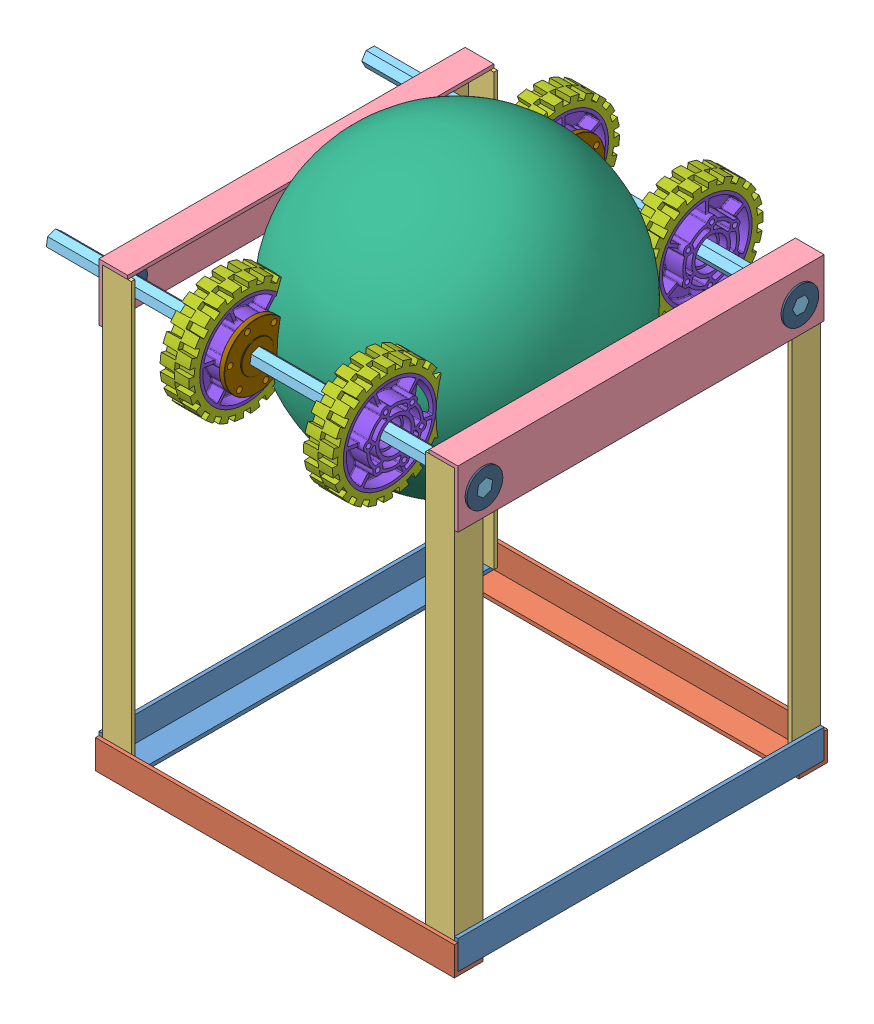
SolidWorks assembly shooter assembly, configuration Default. Lengths in mm.
Overall size (381 483.45 421.01).
33 component instances, 10 part files, 67 mates.
Components (placement in the parent):
- width angle bracket-5: width angle bracket [Default] at origin size (25.4 25.4 323.85)
- width angle bracket-6: width angle bracket [Default] at (317.5 0 323.85) x (-1 0 0) z (0 0 -1) size (25.4 25.4 323.85)
- height angle bracket-1: height angle bracket [Default] at (0 -3.175 327.025) x (0 0 -1) z (1 0 0) size (25.4 25.4 317.5)
- height angle bracket-2: height angle bracket [Default] at (317.5 -3.175 -3.175) x (0 0 1) z (-1 0 0) size (25.4 25.4 317.5)
- length angle bracket-5: length angle bracket [Default] at (314.325 3.175 323.85) x (0 0 -1) z (0 1 0) size (25.4 25.4 381)
- length angle bracket-6: length angle bracket [Default] at (3.175 3.175 323.85) x (1 0 0) z (0 1 0) size (25.4 25.4 381)
- length angle bracket-7: length angle bracket [Default] at (3.175 384.175 0) x (1 0 0) z (0 -1 0) size (25.4 25.4 381)
- length angle bracket-8: length angle bracket [Default] at (314.325 384.175 0) x (0 0 1) z (0 -1 0) size (25.4 25.4 381)
- front width angle-3: front width angle [Default] at (317.5 387.35 323.85) x (0 -1 0) z (0 0 -1) size (50.8 25.4 323.85)
- front width angle-4: front width angle [Default] at (0 387.35 0) x (0 -1 0) z (0 0 1) size (50.8 25.4 323.85)
- shaft-2: shaft [Default] at (319.0748 360.3625 22.225) x (0 -0.036855 -0.999321) z (-1 0 0) size (14.66 12.7 381)
- shaft-3: shaft [Default] at (319.0748 360.3625 301.625) x (0 0.344018 -0.938963) z (-1 0 0) size (14.66 12.7 381)
- ball-1: ball [Default] at (154.804 353.2764 162.3949) size (254 254 254)
- 4 in HiGrip Wheel-1: 4 in HiGrip Wheel [Default] at (103.3017 363.8336 21.178) x (1 0 0) z (0 -0.883864 -0.467743) size (35.12 101.6 101.6)
  - 4 in tread-1: 4 in tread [Default] at (-8.0517 2.5236 2.5343) size (25.4 101.6 101.6)
  - 4in 2013 Hub-1: 4in 2013 Hub [Default] at (-8.0517 2.5236 2.5343) size (35.12 82.55 82.55)
- 4 in HiGrip Wheel-2: 4 in HiGrip Wheel [Default] at (230.3017 361.1665 18.7111) x (1 0 0) z (0 -0.84701 0.531577) size (35.12 101.6 101.6)
  - 4 in tread-1: 4 in tread [Default] at (-8.0517 2.5236 2.5343) size (25.4 101.6 101.6)
  - 4in 2013 Hub-1: 4in 2013 Hub [Default] at (-8.0517 2.5236 2.5343) size (35.12 82.55 82.55)
- 4 in HiGrip Wheel-3: 4 in HiGrip Wheel [Default] at (230.3017 362.3873 298.7367) x (1 0 0) z (0 -0.985175 0.171553) size (35.12 101.6 101.6)
  - 4 in tread-1: 4 in tread [Default] at (-8.0517 2.5236 2.5343) size (25.4 101.6 101.6)
  - 4in 2013 Hub-1: 4in 2013 Hub [Default] at (-8.0517 2.5236 2.5343) size (35.12 82.55 82.55)
- 4 in HiGrip Wheel-4: 4 in HiGrip Wheel [Default] at (103.3017 356.8299 301.2931) x (1 0 0) z (0 0.641157 0.76741) size (35.12 101.6 101.6)
  - 4 in tread-1: 4 in tread [Default] at (-8.0517 2.5236 2.5343) size (25.4 101.6 101.6)
  - 4in 2013 Hub-1: 4in 2013 Hub [Default] at (-8.0517 2.5236 2.5343) size (35.12 82.55 82.55)
- am-0096a+500+Hex+Hub+r2-1: am-0096a+500+Hex+Hub+r2 [Default] at (218.7116 360.3235 301.6576) x (1 0 0) z (0 -0.76741 0.641157) size (25.4 57.15 57.15)
- am-0096a+500+Hex+Hub+r2-2: am-0096a+500+Hex+Hub+r2 [Default] at (218.7116 360.3614 22.1957) x (1 0 0) z (0 -0.467743 0.883864) size (25.4 57.15 57.15)
- am-0096a+500+Hex+Hub+r2-3: am-0096a+500+Hex+Hub+r2 [Default] at (98.7884 360.3914 301.62) x (-1 0 0) z (0 0.76741 -0.641157) size (25.4 57.15 57.15)
- am-0096a+500+Hex+Hub+r2-4: am-0096a+500+Hex+Hub+r2 [Default] at (98.7884 360.4133 22.2231) x (-1 0 0) z (0 -0.999321 0.036855) size (25.4 57.15 57.15)
- .5in hex bearing-1: .5in hex bearing [Default] at (311.15 360.3625 22.225) x (0 0.036855 0.999321) z (0 0.999321 -0.036855) size (31.72 7.92 31.72)
- .5in hex bearing-2: .5in hex bearing [Default] at (311.15 360.3625 301.625) x (0 0.344018 -0.938963) z (0 -0.938963 -0.344018) size (31.72 7.92 31.72)
- .5in hex bearing-3: .5in hex bearing [Default] at (6.35 360.3625 301.625) x (0 -0.985175 0.171553) z (0 -0.171553 -0.985175) size (31.72 7.92 31.72)
- .5in hex bearing-4: .5in hex bearing [Default] at (6.35 360.3625 22.225) x (0 -0.036855 -0.999321) z (0 0.999321 -0.036855) size (31.72 7.92 31.72)
Mates (geometry in assembly coordinates):
- Coincident2: coincident aligned: plane of width angle bracket-5 through (0 0 323.85) normal (-1 0 0); plane of height angle bracket-1 through (0 -3.175 327.025) normal (-1 0 0)
- Coincident3: coincident anti-aligned: plane of width angle bracket-5 through (0 0 323.85) normal (0 0 1); plane of height angle bracket-1 through (317.5 22.225 323.85) normal (0 0 -1)
- Coincident4: coincident anti-aligned: plane of width angle bracket-5 through (0 0 323.85) normal (0 -1 0); plane of height angle bracket-1 through (317.5 0 301.625) normal (0 1 0)
- Coincident7: coincident anti-aligned: plane of width angle bracket-6 through (317.5 0 323.85) normal (0 0 1); plane of height angle bracket-1 through (317.5 22.225 323.85) normal (0 0 -1)
- Coincident8: coincident anti-aligned: plane of width angle bracket-6 through (317.5 0 0) normal (0 -1 0); plane of height angle bracket-1 through (317.5 0 301.625) normal (0 1 0)
- Coincident9: coincident aligned: plane of width angle bracket-6 through (317.5 0 0) normal (1 0 0); plane of height angle bracket-1 through (317.5 -3.175 327.025) normal (1 0 0)
- Coincident10: coincident aligned: plane of width angle bracket-6 through (317.5 0 0) normal (1 0 0); plane of height angle bracket-2 through (317.5 -3.175 -3.175) normal (1 0 0)
- Coincident11: coincident anti-aligned: plane of width angle bracket-6 through (317.5 0 0) normal (0 -1 0); plane of height angle bracket-2 through (0 0 22.225) normal (0 1 0)
- Coincident12: coincident anti-aligned: plane of width angle bracket-6 through (317.5 0 0) normal (0 0 -1); plane of height angle bracket-2 through (0 22.225 0) normal (0 0 1)
- Coincident13: coincident anti-aligned: plane of width angle bracket-6 through (292.1 3.175 0) normal (0 1 0); plane of length angle bracket-5 through (314.325 3.175 323.85) normal (0 -1 0)
- Coincident14: coincident anti-aligned: plane of width angle bracket-6 through (314.325 25.4 0) normal (-1 0 0); plane of length angle bracket-5 through (314.325 384.175 323.85) normal (1 0 0)
- Coincident15: coincident anti-aligned: plane of height angle bracket-1 through (317.5 22.225 323.85) normal (0 0 -1); plane of length angle bracket-5 through (314.325 384.175 323.85) normal (0 0 1)
- Coincident16: coincident anti-aligned: plane of width angle bracket-6 through (292.1 3.175 0) normal (0 1 0); plane of length angle bracket-8 through (314.325 3.175 0) normal (0 -1 0)
- Coincident17: coincident anti-aligned: plane of height angle bracket-2 through (0 22.225 0) normal (0 0 1); plane of length angle bracket-8 through (314.325 3.175 0) normal (0 0 -1)
- Coincident18: coincident anti-aligned: plane of width angle bracket-6 through (314.325 25.4 0) normal (-1 0 0); plane of length angle bracket-8 through (314.325 3.175 0) normal (1 0 0)
- Coincident19: coincident anti-aligned: plane of width angle bracket-5 through (25.4 3.175 323.85) normal (0 1 0); plane of length angle bracket-6 through (3.175 3.175 323.85) normal (0 -1 0)
- Coincident20: coincident anti-aligned: plane of width angle bracket-5 through (3.175 25.4 323.85) normal (1 0 0); plane of length angle bracket-6 through (3.175 384.175 323.85) normal (-1 0 0)
- Coincident21: coincident anti-aligned: plane of height angle bracket-1 through (317.5 22.225 323.85) normal (0 0 -1); plane of length angle bracket-6 through (3.175 384.175 323.85) normal (0 0 1)
- Coincident22: coincident anti-aligned: plane of width angle bracket-5 through (25.4 3.175 323.85) normal (0 1 0); plane of length angle bracket-7 through (3.175 3.175 0) normal (0 -1 0)
- Coincident23: coincident anti-aligned: plane of width angle bracket-5 through (3.175 25.4 323.85) normal (1 0 0); plane of length angle bracket-7 through (3.175 3.175 0) normal (-1 0 0)
- Coincident24: coincident anti-aligned: plane of height angle bracket-2 through (0 22.225 0) normal (0 0 1); plane of length angle bracket-7 through (3.175 3.175 0) normal (0 0 -1)
- Coincident25: coincident anti-aligned: plane of length angle bracket-5 through (314.325 384.175 323.85) normal (1 0 0); plane of front width angle-3 through (314.325 336.55 0) normal (-1 0 0)
- Coincident26: coincident anti-aligned: plane of length angle bracket-5 through (314.325 384.175 323.85) normal (0 1 0); plane of front width angle-3 through (292.1 384.175 0) normal (0 -1 0)
- Coincident27: coincident aligned: plane of length angle bracket-8 through (314.325 3.175 0) normal (0 0 -1); plane of front width angle-3 through (317.5 387.35 0) normal (0 0 -1)
- Coincident28: coincident anti-aligned: plane of length angle bracket-7 through (3.175 3.175 0) normal (-1 0 0); plane of front width angle-4 through (3.175 336.55 323.85) normal (1 0 0)
- Coincident29: coincident aligned: plane of length angle bracket-7 through (3.175 3.175 0) normal (0 0 -1); plane of front width angle-4 through (0 387.35 0) normal (0 0 -1)
- Coincident30: coincident anti-aligned: plane of length angle bracket-7 through (3.175 384.175 0) normal (0 1 0); plane of front width angle-4 through (25.4 384.175 323.85) normal (0 -1 0)
- Distance1: distance = 101.6 mm anti-aligned: plane of 4 in HiGrip Wheel-2/4 in tread-1 through (209.55 360.3614 22.1957) normal (-1 0 0); plane of 4 in HiGrip Wheel-1/4 in tread-1 through (107.95 360.4133 22.2231) normal (1 0 0)
- Width1: width anti-aligned: plane of front width angle-3 through (317.5 387.35 0) normal (1 0 0); plane of front width angle-4 through (0 387.35 323.85) normal (-1 0 0); plane of 4 in HiGrip Wheel-1/4 in tread-1 through (82.55 360.4133 22.2231) normal (-1 0 0); plane of 4 in HiGrip Wheel-2/4 in tread-1 through (234.95 360.3614 22.1957) normal (1 0 0)
- Coincident44: coincident aligned: plane of 4 in HiGrip Wheel-2/4 in tread-1 through (234.95 360.3614 22.1957) normal (1 0 0); plane of 4 in HiGrip Wheel-3/4 in tread-1 through (234.95 360.3235 301.6576) normal (1 0 0)
- Coincident45: coincident aligned: plane of 4 in HiGrip Wheel-1/4 in tread-1 through (82.55 360.4133 22.2231) normal (-1 0 0); plane of 4 in HiGrip Wheel-4/4 in tread-1 through (82.55 360.3914 301.62) normal (-1 0 0)
- Concentric7: concentric anti-aligned: cylinder of 4 in HiGrip Wheel-3/4in 2013 Hub-1 through (204.7875 360.3235 301.6576) axis (1 0 0) radius 12.2174; cylinder of am-0096a+500+Hex+Hub+r2-1 through (224.7265 360.3235 301.6576) axis (-1 0 0) radius 12.1666
- Coincident46: coincident anti-aligned: plane of 4 in HiGrip Wheel-3/4in 2013 Hub-1 through (204.7875 360.3235 301.6576) normal (-1 0 0); plane of am-0096a+500+Hex+Hub+r2-1 through (204.7875 355.929 305.3291) normal (1 0 0)
- Concentric8: concentric aligned: cylinder of 4 in HiGrip Wheel-3/4in 2013 Hub-1 through (204.7875 364.4086 325.1171) axis (1 0 0) radius 2.159; cylinder of am-0096a+500+Hex+Hub+r2-1 through (205.6765 364.4086 325.1171) axis (1 0 0) radius 2.5908
- Coincident47: coincident anti-aligned: plane of shaft-3 through (-61.9252 362.885 294.7402) normal (0 -0.171553 -0.985175); plane of am-0096a+500+Hex+Hub+r2-1 through (199.3265 355.6035 296.0081) normal (0 0.171553 0.985175)
- Coincident49: coincident anti-aligned: plane of shaft-3 through (-61.9252 365.0637 307.2519) normal (0 0.938963 0.344018); plane of am-0096a+500+Hex+Hub+r2-1 through (199.3265 367.5761 300.3947) normal (0 -0.938963 -0.344018)
- Concentric9: concentric aligned: cylinder of 4 in HiGrip Wheel-4/4in 2013 Hub-1 through (77.7875 360.3914 301.62) axis (1 0 0) radius 12.2174; cylinder of am-0096a+500+Hex+Hub+r2-3 through (92.7735 360.3914 301.62) axis (1 0 0) radius 12.1666
- Coincident50: coincident anti-aligned: plane of 4 in HiGrip Wheel-4/4in 2013 Hub-1 through (112.7125 360.3914 301.62) normal (1 0 0); plane of am-0096a+500+Hex+Hub+r2-3 through (112.7125 364.7859 297.9485) normal (-1 0 0)
- Concentric10: concentric anti-aligned: cylinder of 4 in HiGrip Wheel-4/4in 2013 Hub-1 through (77.7875 364.4765 325.0795) axis (1 0 0) radius 2.159; cylinder of am-0096a+500+Hex+Hub+r2-3 through (111.8235 364.4765 325.0795) axis (-1 0 0) radius 2.5908
- Coincident51: coincident anti-aligned: plane of shaft-3 through (-61.9252 355.6613 295.9981) normal (0 -0.938963 -0.344018); plane of am-0096a+500+Hex+Hub+r2-3 through (118.1735 355.6714 295.9705) normal (0 0.938963 0.344018)
- Coincident52: coincident anti-aligned: plane of shaft-3 through (-61.9252 353.1389 302.8829) normal (0 -0.76741 0.641157); plane of am-0096a+500+Hex+Hub+r2-3 through (118.1735 353.1389 302.8829) normal (0 0.76741 -0.641157)
- Concentric11: concentric anti-aligned: cylinder of 4 in HiGrip Wheel-2/4in 2013 Hub-1 through (204.7875 360.3614 22.1957) axis (1 0 0) radius 12.2174; cylinder of am-0096a+500+Hex+Hub+r2-2 through (224.7265 360.3614 22.1957) axis (-1 0 0) radius 12.1666
- Coincident53: coincident anti-aligned: plane of 4 in HiGrip Wheel-2/4in 2013 Hub-1 through (204.7875 360.3614 22.1957) normal (-1 0 0); plane of am-0096a+500+Hex+Hub+r2-2 through (204.7875 357.683 27.257) normal (1 0 0)
- Concentric12: concentric aligned: cylinder of 4 in HiGrip Wheel-2/4in 2013 Hub-1 through (204.7875 373.0196 42.3651) axis (1 0 0) radius 2.159; cylinder of am-0096a+500+Hex+Hub+r2-2 through (205.6765 373.0196 42.3651) axis (1 0 0) radius 2.5908
- Concentric13: concentric aligned: cylinder of 4 in HiGrip Wheel-1/4in 2013 Hub-1 through (77.7875 360.4133 22.2231) axis (1 0 0) radius 12.2174; cylinder of am-0096a+500+Hex+Hub+r2-4 through (92.7735 360.4133 22.2231) axis (1 0 0) radius 12.1666
- Coincident54: coincident anti-aligned: plane of 4 in HiGrip Wheel-1/4in 2013 Hub-1 through (112.7125 360.4133 22.2231) normal (1 0 0); plane of am-0096a+500+Hex+Hub+r2-4 through (112.7125 354.6908 22.4342) normal (-1 0 0)
- Concentric14: concentric anti-aligned: cylinder of 4 in HiGrip Wheel-1/4in 2013 Hub-1 through (77.7875 384.2096 21.3455) axis (1 0 0) radius 2.159; cylinder of am-0096a+500+Hex+Hub+r2-4 through (111.8235 384.2096 21.3455) axis (-1 0 0) radius 2.5908
- Coincident55: coincident anti-aligned: plane of shaft-2 through (-61.9252 354.1519 26.1227) normal (0 -0.467743 0.883864); plane of am-0096a+500+Hex+Hub+r2-2 through (199.3265 360.6327 29.5524) normal (0 0.467743 -0.883864)
- Coincident56: coincident anti-aligned: plane of shaft-2 through (-61.9252 360.6327 29.5524) normal (0 0.531577 0.84701); plane of am-0096a+500+Hex+Hub+r2-2 through (199.3265 366.8681 25.6391) normal (0 -0.531577 -0.84701)
- Coincident57: coincident anti-aligned: plane of shaft-2 through (-61.9252 360.0923 14.8976) normal (0 -0.531577 -0.84701); plane of am-0096a+500+Hex+Hub+r2-4 through (118.1735 360.142 14.8665) normal (0 0.531577 0.84701)
- Coincident59: coincident anti-aligned: plane of shaft-2 through (-61.9252 354.1519 26.1227) normal (0 -0.467743 0.883864); plane of am-0096a+500+Hex+Hub+r2-4 through (118.1735 354.1779 26.1364) normal (0 0.467743 -0.883864)
- Concentric15: concentric aligned: cylinder of front width angle-3 through (317.5 360.3625 22.225) axis (-1 0 0) radius 14.2875; cylinder of .5in hex bearing-1 through (319.0748 360.3625 22.225) axis (-1 0 0) radius 14.2875
- Coincident60: coincident anti-aligned: plane of front width angle-3 through (317.5 387.35 0) normal (1 0 0); plane of .5in hex bearing-1 through (317.5 360.3625 22.225) normal (-1 0 0)
- Coincident61: coincident anti-aligned: plane of shaft-2 through (-61.9252 366.8433 25.6547) normal (0 0.999321 -0.036855); plane of .5in hex bearing-1 through (319.0748 366.5731 18.3273) normal (0 -0.999321 0.036855)
- Coincident62: coincident anti-aligned: plane of shaft-2 through (-61.9252 360.6327 29.5524) normal (0 0.531577 0.84701); plane of .5in hex bearing-1 through (319.0748 366.8433 25.6547) normal (0 -0.531577 -0.84701)
- Concentric16: concentric aligned: cylinder of front width angle-3 through (317.5 360.3625 301.625) axis (-1 0 0) radius 14.2875; cylinder of .5in hex bearing-2 through (319.0748 360.3625 301.625) axis (-1 0 0) radius 14.2875
- Coincident63: coincident anti-aligned: plane of front width angle-3 through (317.5 387.35 0) normal (1 0 0); plane of .5in hex bearing-2 through (317.5 360.3625 301.625) normal (-1 0 0)
- Coincident64: coincident anti-aligned: plane of shaft-3 through (-61.9252 353.1389 302.8829) normal (0 -0.76741 0.641157); plane of .5in hex bearing-2 through (319.0748 357.84 308.5098) normal (0 0.76741 -0.641157)
- Coincident65: coincident anti-aligned: plane of shaft-3 through (-61.9252 357.84 308.5098) normal (0 0.171553 0.985175); plane of .5in hex bearing-2 through (319.0748 365.0637 307.2519) normal (0 -0.171553 -0.985175)
- Concentric17: concentric aligned: cylinder of front width angle-4 through (0 360.3625 301.625) axis (1 0 0) radius 14.2875; cylinder of .5in hex bearing-3 through (-1.5748 360.3625 301.625) axis (1 0 0) radius 14.2875
- Coincident66: coincident anti-aligned: plane of front width angle-4 through (0 387.35 323.85) normal (-1 0 0); plane of .5in hex bearing-3 through (0 360.3625 301.625) normal (1 0 0)
- Concentric18: concentric aligned: cylinder of front width angle-4 through (0 360.3625 22.225) axis (1 0 0) radius 14.2875; cylinder of .5in hex bearing-4 through (-1.5748 360.3625 22.225) axis (1 0 0) radius 14.2875
- Coincident67: coincident anti-aligned: plane of front width angle-4 through (0 387.35 323.85) normal (-1 0 0); plane of .5in hex bearing-4 through (0 360.3625 22.225) normal (1 0 0)
- Coincident68: coincident anti-aligned: plane of shaft-2 through (-61.9252 360.6327 29.5524) normal (0 0.531577 0.84701); plane of .5in hex bearing-4 through (-1.5748 360.6327 29.5524) normal (0 -0.531577 -0.84701)
- Parallel2: parallel anti-aligned: plane of shaft-3 through (-61.9252 355.6613 295.9981) normal (0 -0.938963 -0.344018); plane of .5in hex bearing-3 through (-1.5748 355.6613 295.9981) normal (0 0.938963 0.344018)
- Coincident70: coincident aligned: plane of shaft-2 through (319.0748 360.3625 22.225) normal (1 0 0); plane of .5in hex bearing-1 through (319.0748 360.3625 22.225) normal (1 0 0)
- Coincident71: coincident aligned: plane of shaft-3 through (319.0748 360.3625 301.625) normal (1 0 0); plane of .5in hex bearing-2 through (319.0748 360.3625 301.625) normal (1 0 0)
